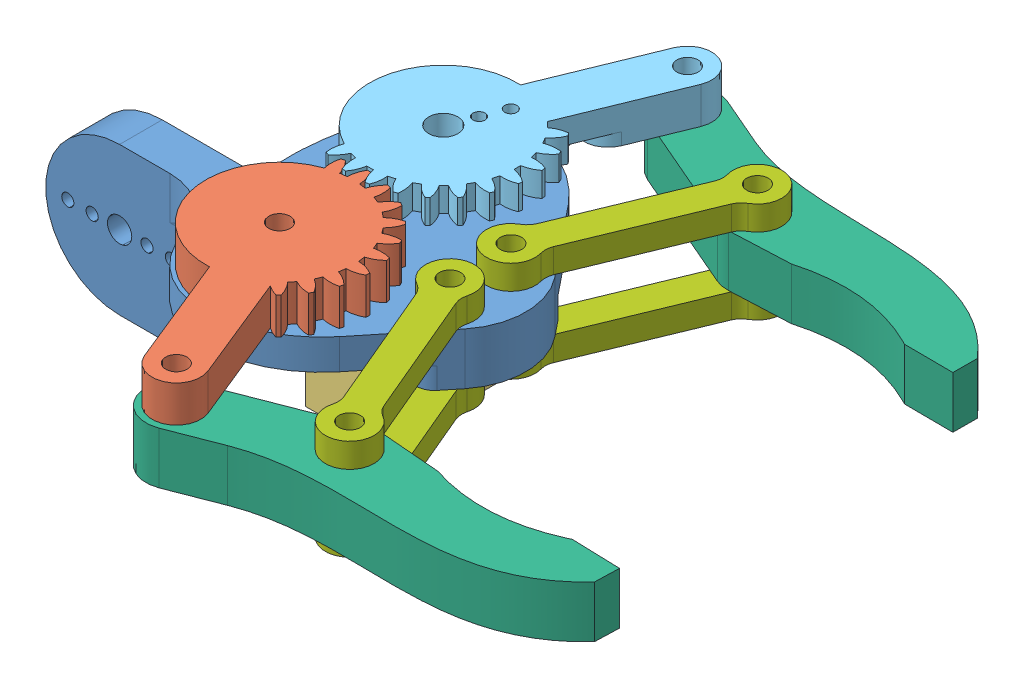
SolidWorks assembly Gripper Assem 1, configuration Default. Lengths in mm.
Overall size (116.36 34.9 119.52).
11 component instances, 7 part files, 21 mates.
Components (placement in the parent):
- Base-1: Base [Default] at (-0.4564 37.421 56.877) size (69.33 24.3 52.4)
- Gear Arm 1-1: Gear Arm 1 [Default] at (33.5435 51.5558 77.1918) x (0.375988 0 0.926624) z (-0.926624 0 0.375988) size (49.29 6 26.63)
- Servo Micro-1: Servo Micro [Default] at (29.7436 21.0058 46.027) x (0 0 1) z (-1 0 0) size (32.6 29.9 12.4)
- Microservo horn-1: Microservo horn [По умолчанию] at (29.7436 51.9058 40.927) x (-0.377866 0 0.92586) z (0 -1 0) size (19.75 7.5 5)
- Gear Arm 2-1: Gear Arm 2 [Default] at (24.7361 51.9058 49.7055) x (-0.495482 0 0.868618) z (-0.868618 0 -0.495482) size (49.02 6 26.63)
- Grip-1: Grip [Default] at (34.8373 49.5558 93.4632) x (0 -1 0) z (-0.932545 0 0.361055) size (8.5 22.22 65.31)
- Grip-2: Grip [Default] at (34.7917 41.0558 15.0679) x (0 1 0) z (-0.918243 0 -0.396018) size (8.5 22.22 65.31)
- Link-1: Link [Default] at (49.7436 53.5558 59.827) x (0.389601 0 0.920984) z (0.920984 0 -0.389601) size (39 4 8)
- Link-2: Link [Default] at (49.7436 49.5558 49.827) x (0.381314 0 -0.924446) z (0.924446 0 0.381314) size (39 4 8)
- Link-3: Link [Default] at (49.7436 37.0558 59.827) x (0.389601 0 0.920984) z (-0.920984 0 0.389601) size (39 4 8)
- Link-4: Link [Default] at (61.5644 41.0558 21.1692) x (-0.381314 0 0.924446) z (0.924446 0 0.381314) size (39 4 8)
Mates (geometry in assembly coordinates):
- Coincident1: coincident aligned: circle of Base-1; circle of Gear Arm 1-1
- Concentric3: concentric anti-aligned: circle of Base-1; circle of Servo Micro-1
- Concentric4: concentric anti-aligned: circle of Base-1; circle of Servo Micro-1
- Coincident3: coincident anti-aligned: plane of Base-1 through (-0.4564 39.0558 56.877) normal (0 -1 0); plane of Servo Micro-1 through (23.5436 39.0558 62.327) normal (0 1 0)
- Concentric5: concentric aligned: circle of Servo Micro-1; circle of Microservo horn-1
- Coincident4: coincident anti-aligned: plane of Servo Micro-1 through (29.7436 50.9058 40.927) normal (0 1 0); plane of Microservo horn-1 through (29.7436 50.9058 40.927) normal (0 -1 0)
- Concentric6: concentric aligned: circle of Microservo horn-1; circle of Gear Arm 2-1
- Concentric7: concentric anti-aligned: circle of Microservo horn-1; circle of Gear Arm 2-1
- Concentric8: concentric anti-aligned: circle of Microservo horn-1; circle of Gear Arm 2-1
- Coincident5: coincident anti-aligned: plane of Microservo horn-1 through (29.7436 51.9058 40.927) normal (0 1 0); plane of Gear Arm 2-1 through (14.5076 51.9058 67.637) normal (0 -1 0)
- GearMate1: gear = 26.9 : 26.9 mm: circle of Gear Arm 2-1; circle of Gear Arm 1-1
- Coincident6: coincident anti-aligned: circle of Gear Arm 1-1; circle of Grip-1
- Coincident8: coincident anti-aligned: circle of Base-1; circle of Link-1
- Coincident9: coincident aligned: circle of Grip-1; circle of Link-1
- Coincident10: coincident aligned: circle of Base-1; circle of Link-2
- Coincident15: coincident aligned: circle of Grip-2; circle of Link-2
- Concentric10: concentric anti-aligned: circle of Gear Arm 2-1; circle of Grip-2
- Coincident16: coincident anti-aligned: circle of Grip-1; circle of Link-3
- Concentric12: concentric anti-aligned: circle of Base-1; circle of Link-3
- Coincident19: coincident anti-aligned: circle of Grip-2; circle of Link-4
- Coincident20: coincident aligned: circle of Base-1; circle of Link-4
